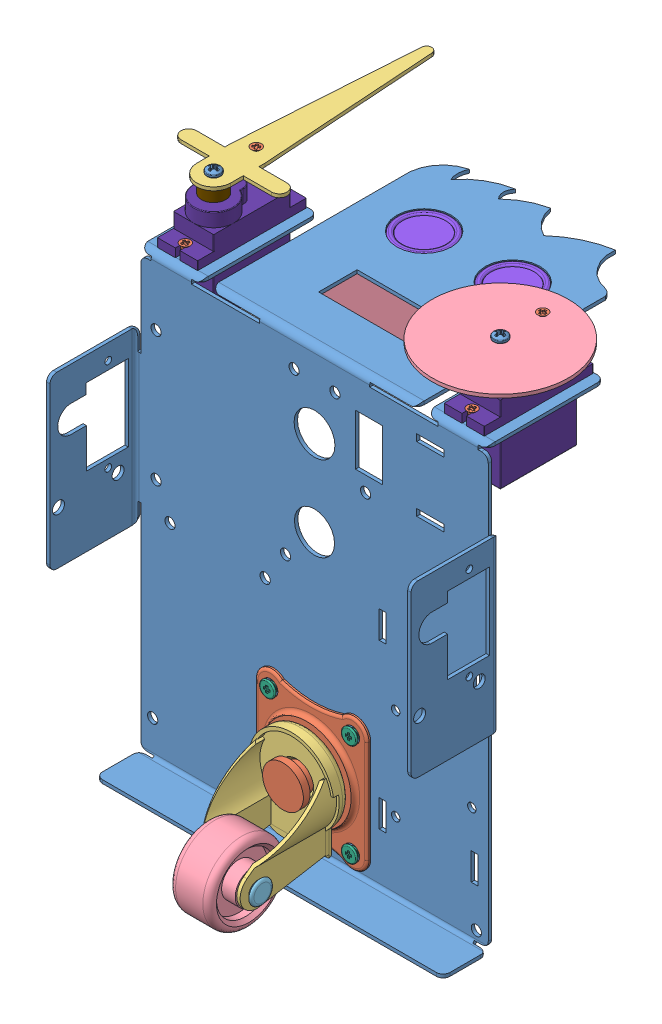
SolidWorks assembly MS_OL_AC, configuration Predeterminado. Lengths in mm.
Overall size (119.83 152.05 114.03).
59 component instances, 22 part files, 13 mates.
Components (placement in the parent):
- DYOR_OLED_MetalSheet_Accessory-1: DYOR_OLED_MetalSheet_Accessory [Predeterminado] at (90.3983 -137.9363 139.7994) size (107.01 129.28 94.67)
- CA-1: CA [Predeterminado] at (2.8546 2.4966 1.124) size (33 45.94 42.59)
  - Caster Wheel-1: Caster Wheel [Default] at (194.2283 -297.83 183.8938) x (0 1 0) z (-1 0 0) size (45.94 37.59 33)
    - caster holder-1: caster holder [Default] at (-24.0751 44.7184 29.5137) x (1 0 0) z (0 0 -1) size (39 9.27 33)
    - holder-1: holder [Default] at (-1.5751 42.9484 46.0137) x (0 0 1) z (1 0 0) size (25 28.07 31.31)
    - caster wheel-1: caster wheel [Default] at (-15.6961 19.9484 46.0137) x (0.997275 0.073773 0) z (0 0 1) size (23 23 14)
    - Part4-1: Part4 [Default] at (-15.6961 19.9484 55.0137) x (-0.978448 0.206495 0) z (0 0 -1) size (7 7 20)
  - M3x6 SelfTap Screw-1: M3x6 SelfTap Screw [Predeterminado] at (136.2146 -284.4051 140.6754) size (4.62 4.62 7)
  - M3x6 SelfTap Screw-2: M3x6 SelfTap Screw [Predeterminado] at (136.2146 -314.4051 140.6754) size (4.62 4.62 7)
  - M3x6 SelfTap Screw-3: M3x6 SelfTap Screw [Predeterminado] at (160.2146 -284.4051 140.6754) size (4.62 4.62 7)
  - M3x6 SelfTap Screw-4: M3x6 SelfTap Screw [Predeterminado] at (160.2146 -314.4051 140.6754) size (4.62 4.62 7)
- HC-SR04 Ping Sensor-1: HC-SR04 Ping Sensor [Default] at (151.0973 -203.2073 94.6556) x (0 0 -1) z (0 1 0) size (25.18 45 18.07)
  - PCB-1: PCB [Default] at origin size (20.5 45 1.75)
  - Transducer-1: Transducer [Default] at (0 -13 13.25) x (1 0 0) z (0 -1 0) size (15.88 12 15.88)
  - Transducer-2: Transducer [Default] at (0 13 13.25) x (1 0 0) z (0 -1 0) size (15.88 12 15.88)
  - 3 Pin Header 90 Degree-1: 3 Pin Header 90 Degree [Default] at (8.4275 0 -1.25) x (-1 0 0) z (0 -1 0) size (8 7.82 10)
  - 14 Pin SMT-1: 14 Pin SMT [Default] at (-0.35 -18.5 -0.85) x (0 -1 0) z (1 0 0) size (6 1.6 8.8)
  - 14 Pin SMT-2: 14 Pin SMT [Default] at (0 -0.3826 -0.85) x (1 0 0) z (0 1 0) size (6 1.6 8.8)
  - 14 Pin SMT-3: 14 Pin SMT [Default] at (0 17.5274 -0.85) x (1 0 0) z (0 1 0) size (6 1.6 8.8)
  - Cap1 SMT-1: Cap1 SMT [Default] at (-1.755 7.4774 -0.9689) x (0 1 0) z (-1 0 0) size (4.5 1.84 1.75)
  - Cap1 SMT-2: Cap1 SMT [Default] at (6.835 7.4774 -0.9689) x (0 1 0) z (-1 0 0) size (4.5 1.84 1.75)
  - Cap1 SMT-3: Cap1 SMT [Default] at (-6.835 7.4774 -0.9689) x (0 1 0) z (-1 0 0) size (4.5 1.84 1.75)
  - Cap1 SMT-4: Cap1 SMT [Default] at (4.295 7.4774 -0.9689) x (0 1 0) z (-1 0 0) size (4.5 1.84 1.75)
  - Cap1 SMT-5: Cap1 SMT [Default] at (1.755 7.4774 -0.9689) x (0 1 0) z (-1 0 0) size (4.5 1.84 1.75)
  - Cap1 SMT-6: Cap1 SMT [Default] at (-4.295 7.4774 -0.9689) x (0 1 0) z (-1 0 0) size (4.5 1.84 1.75)
  - HC-SR04 Crystal-1: HC-SR04 Crystal [Default] at (-8.3 0 1.75) x (0 -1 0) z (0 0 1) size (10 3.5 2.7)
- OLED_0.91_128x32-1: OLED_0.91_128x32 [Predeterminado] at (152.1882 -192.9673 119.9615) x (1 0 0) z (0 1 0) size (38.3 12.1 11.46)
  - OLED_0.91_128x32.stp-1: OLED_0.91_128x32.stp [Predeterminado] at origin size (38.3 12.1 11.46)
    - OLED_0.91_128x32.stp-1: OLED_0.91_128x32.stp [Predeterminado] at origin size (38.3 12.1 2.57)
    - Pin Header 4 x 1 TH 2.54mm Pitch.stp-1: Pin Header 4 x 1 TH 2.54mm Pitch.stp [Predeterminado] at (-17.55 -3.81 -2.6) size (2.54 10.16 11.43)
    - RESC-0603.stp-1: RESC-0603.stp [Predeterminado] at (4.3 -5.3 0) x (1 0 0) z (0 0 -1) size (1.7 0.9 0.55)
    - RESC-0603.stp-2: RESC-0603.stp [Predeterminado] at (4.3 -3.8 0) x (1 0 0) z (0 0 -1) size (1.7 0.9 0.55)
    - RESC-0603.stp-3: RESC-0603.stp [Predeterminado] at (4.3 -2.3 0) x (1 0 0) z (0 0 -1) size (1.7 0.9 0.55)
    - RESC-0603.stp-4: RESC-0603.stp [Predeterminado] at (4.3 -0.8 0) x (1 0 0) z (0 0 -1) size (1.7 0.9 0.55)
    - RESC-0603.stp-5: RESC-0603.stp [Predeterminado] at (4.3 0.7 0) x (1 0 0) z (0 0 -1) size (1.7 0.9 0.55)
    - RESC-0603.stp-6: RESC-0603.stp [Predeterminado] at (4.3 2.2 0) x (1 0 0) z (0 0 -1) size (1.7 0.9 0.55)
    - RESC-0603.stp-7: RESC-0603.stp [Predeterminado] at (4.3 3.7 0) x (1 0 0) z (0 0 -1) size (1.7 0.9 0.55)
    - RESC-0603.stp-8: RESC-0603.stp [Predeterminado] at (4.3 5.2 0) x (1 0 0) z (0 0 -1) size (1.7 0.9 0.55)
    - RESC-0603.stp-9: RESC-0603.stp [Predeterminado] at (-1.4 -3.06 0) x (1 0 0) z (0 0 -1) size (1.7 0.9 0.55)
    - RESC-0603.stp-10: RESC-0603.stp [Predeterminado] at (-1.4 -1.56 0) x (1 0 0) z (0 0 -1) size (1.7 0.9 0.55)
    - RESC-0603.stp-11: RESC-0603.stp [Predeterminado] at (-1.4 -0.06 0) x (1 0 0) z (0 0 -1) size (1.7 0.9 0.55)
    - RESC-0603.stp-12: RESC-0603.stp [Predeterminado] at (-1.4 1.44 0) x (1 0 0) z (0 0 -1) size (1.7 0.9 0.55)
    - RESC-0603.stp-13: RESC-0603.stp [Predeterminado] at (-1.4 2.94 0) x (1 0 0) z (0 0 -1) size (1.7 0.9 0.55)
    - 2SD0601A.stp-1: 2SD0601A.stp [Predeterminado] at (-9.8 -1.3 -0.08) x (1 0 0) z (0 1 0) size (2.76 1.18 2.9)
- AC-1: AC [Predeterminado] at (4.3283 -9.6438 -1.0225) size (119.83 34.06 84.1)
  - sg90-1: sg90 [Default] at (182.9409 -195.7135 134.2781) x (0 0 -1) z (1 0 0) size (31.9 29.9 11.8)
  - sg90-2: sg90 [Default] at (98.7972 -195.7135 134.2781) x (0 0 -1) z (1 0 0) size (31.9 29.9 11.8)
  - SG90 plastic Horn-1: SG90 plastic Horn [Default] at (188.8409 -166.2635 128.3781) x (-0.029359 0 -0.999569) z (0.999569 0 -0.029359) size (19.4 4 7.07)
  - SG90 plastic Horn-2: SG90 plastic Horn [Default] at (104.6972 -166.2635 128.3781) x (-0.012387 0 -0.999923) z (0.999923 0 -0.012387) size (19.4 4 7.07)
  - (M2_3_mm)_90116A007_METRIC 316 SS PAN HEAD PHILLIPS MACHINE SCREW-1: (M2_3_mm)_90116A007_METRIC 316 SS PAN HEAD PHILLIPS MACHINE SCREW [90116A007] at (104.6972 -166.2635 128.3781) x (-1 0 0) z (0 1 0) size (4 4 4.68)
  - (M2_3_mm)_90116A007_METRIC 316 SS PAN HEAD PHILLIPS MACHINE SCREW-2: (M2_3_mm)_90116A007_METRIC 316 SS PAN HEAD PHILLIPS MACHINE SCREW [90116A007] at (188.8409 -166.2635 128.3781) x (-1 0 0) z (0 1 0) size (4 4 4.68)
  - M2x6 SelfTap Screw-1: M2x6 SelfTap Screw [Predeterminado] at (104.6972 -162.7635 115.8781) x (0.825172 0 -0.564882) z (0 1 0) size (3.4 3.28 6)
  - M2x6 SelfTap Screw-2: M2x6 SelfTap Screw [Predeterminado] at (188.7787 -162.7635 115.8783) x (0.001298 0 -0.999999) z (0 1 0) size (3.4 3.28 6)
  - M2x6 SelfTap Screw-3: M2x6 SelfTap Screw [Predeterminado] at (104.6972 -176.8135 109.3781) x (-0.923728 0 -0.383049) z (0 1 0) size (3.4 3.28 6)
  - M2x6 SelfTap Screw-4: M2x6 SelfTap Screw [Predeterminado] at (104.6972 -176.8135 136.6781) x (-0.923728 0 -0.383049) z (0 1 0) size (3.4 3.28 6)
  - M2x6 SelfTap Screw-5: M2x6 SelfTap Screw [Predeterminado] at (188.8409 -176.8135 136.6781) x (0.923728 0 0.383049) z (0 1 0) size (3.4 3.28 6)
  - M2x6 SelfTap Screw-6: M2x6 SelfTap Screw [Predeterminado] at (188.8409 -176.8135 109.3781) x (0.923728 0 0.383049) z (0 1 0) size (3.4 3.28 6)
  - Sword-1: Sword [Predeterminado] at (59.4912 -163.2635 112.6165) x (1 0 0) z (0 1 0) size (31.17 69 1)
  - Shield-1: Shield [Predeterminado] at (233.9679 -164.2635 112.3919) x (-0.999988 0 0.004973) z (0 -1 0) size (40 40 1)
Mates (geometry in assembly coordinates):
- Concéntrica339: concentric: circle of DYOR_OLED_MetalSheet_Accessory-1; circle of ?
- Concéntrica340: concentric: circle of DYOR_OLED_MetalSheet_Accessory-1; circle of ?
- Concéntrica341: concentric: circle of DYOR_OLED_MetalSheet_Accessory-1; circle of HC-SR04 Ping Sensor-1/Transducer-1
- Paralelo107: parallel: plane of DYOR_OLED_MetalSheet_Accessory-1 through (102.0691 -189.0132 138.7994) normal (0 0 -1); plane of HC-SR04 Ping Sensor-1/PCB-1 through (128.5973 -201.4573 104.9056) normal (0 0 1)
- Coincidente593: coincident: plane of DYOR_OLED_MetalSheet_Accessory-1 through (102.0691 -189.4573 137.7115) normal (0 1 0); plane of HC-SR04 Ping Sensor-1/Transducer-1 through (164.0973 -189.4573 86.7156) normal (0 1 0)
- Coincidente594: coincident: plane of DYOR_OLED_MetalSheet_Accessory-1 through (102.0691 -190.4573 137.7115) normal (0 -1 0); plane of OLED_0.91_128x32-1/OLED_0.91_128x32.stp-1/OLED_0.91_128x32.stp-1 through (150.9882 -190.4573 119.9615) normal (0 1 0)
- Coincidente597: coincident: plane of DYOR_OLED_MetalSheet_Accessory-1 through (102.0691 -189.4573 137.7115) normal (0 1 0); plane of AC-1/sg90-1 through (199.0691 -189.4573 106.0556) normal (0 -1 0)
- Coincidente598: coincident: plane of DYOR_OLED_MetalSheet_Accessory-1 through (102.0691 -189.0132 139.7994) normal (0 0 1); plane of CA-1/Caster Wheel-1/caster holder-1 through (151.0691 -252.1104 139.7994) normal (0 0 -1)
- Coincidente599: coincident: plane of DYOR_OLED_MetalSheet_Accessory-1 through (138.0882 -190.4573 114.3115) normal (1 0 0); plane of OLED_0.91_128x32-1/OLED_0.91_128x32.stp-1/OLED_0.91_128x32.stp-1 through (138.0882 -190.5173 114.3115) normal (-1 0 0)
- Coincidente600: coincident: plane of DYOR_OLED_MetalSheet_Accessory-1 through (163.8882 -190.4573 114.3115) normal (0 0 1); line of OLED_0.91_128x32-1/OLED_0.91_128x32.stp-1/OLED_0.91_128x32.stp-1 through (138.0882 -190.5173 114.3115) axis (1 0 0)
- Coincidente601: coincident: plane of DYOR_OLED_MetalSheet_Accessory-1 through (199.0691 -190.4573 133.2556) normal (-1 0 0); plane of AC-1/sg90-1 through (199.0691 -205.3573 133.2556) normal (1 0 0)
- Concéntrica342: concentric: circle of DYOR_OLED_MetalSheet_Accessory-1; circle of CA-1/Caster Wheel-1/caster holder-1
- Concéntrica343: concentric: circle of DYOR_OLED_MetalSheet_Accessory-1; circle of AC-1/M2x6 SelfTap Screw-6
